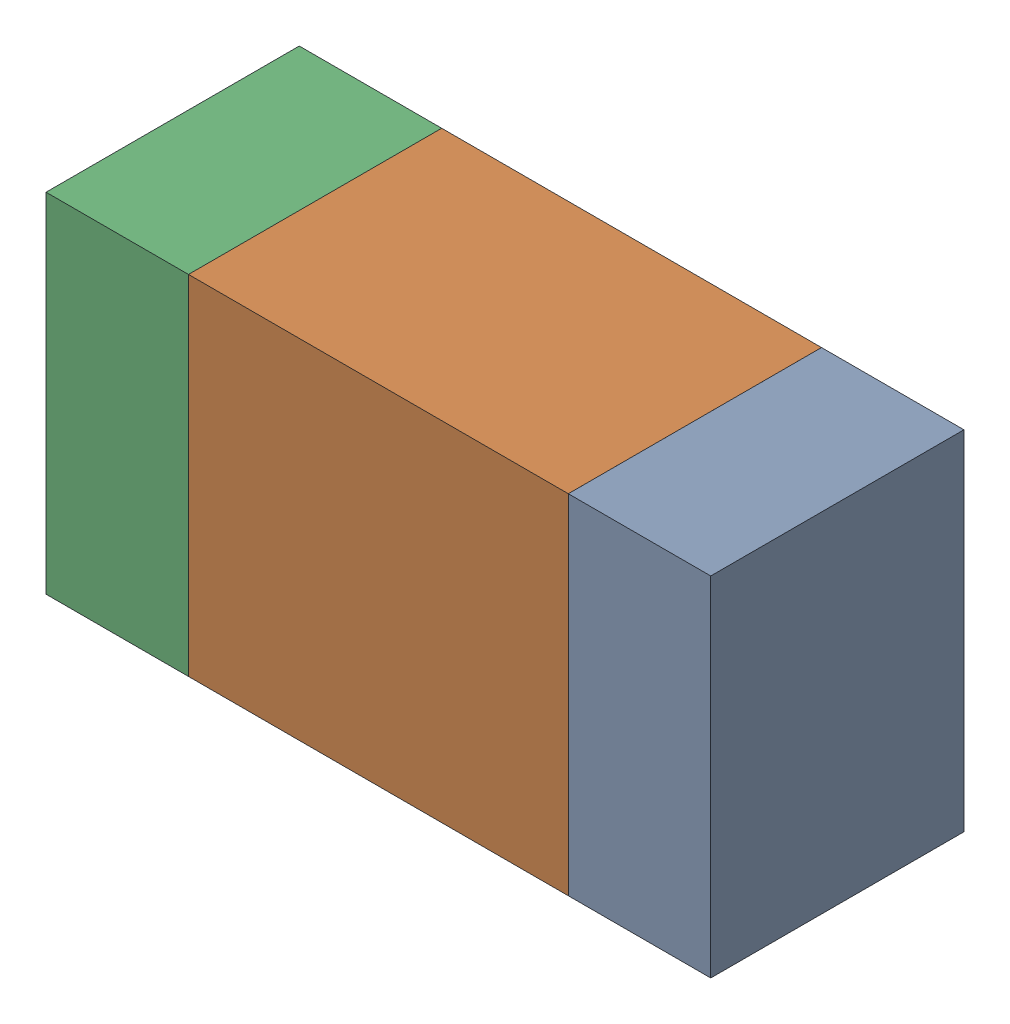
SolidWorks assembly R505_2PCB, configuration Default. Lengths in mm.
Overall size (1.05 0.55 0.4).
6 component instances, 2 part files, 0 mates.
Components (placement in the parent):
- 854785432-1: 854785432 [Default] at (151.3878 85.8681 0) size (0.22 0.55 0.4)
  - Extruded-1: Extruded [Default] at origin size (0.22 0.55 0.4)
- 854785568-1: 854785568 [Default] at (150.9753 85.8681 0) size (0.6 0.55 0.4)
  - Extruded_2-1: Extruded_2 [Default] at origin size (0.6 0.55 0.4)
- 854785432-2: 854785432 [Default] at (150.5628 85.8681 0) size (0.22 0.55 0.4)
  - Extruded-1: Extruded [Default] at origin size (0.22 0.55 0.4)
